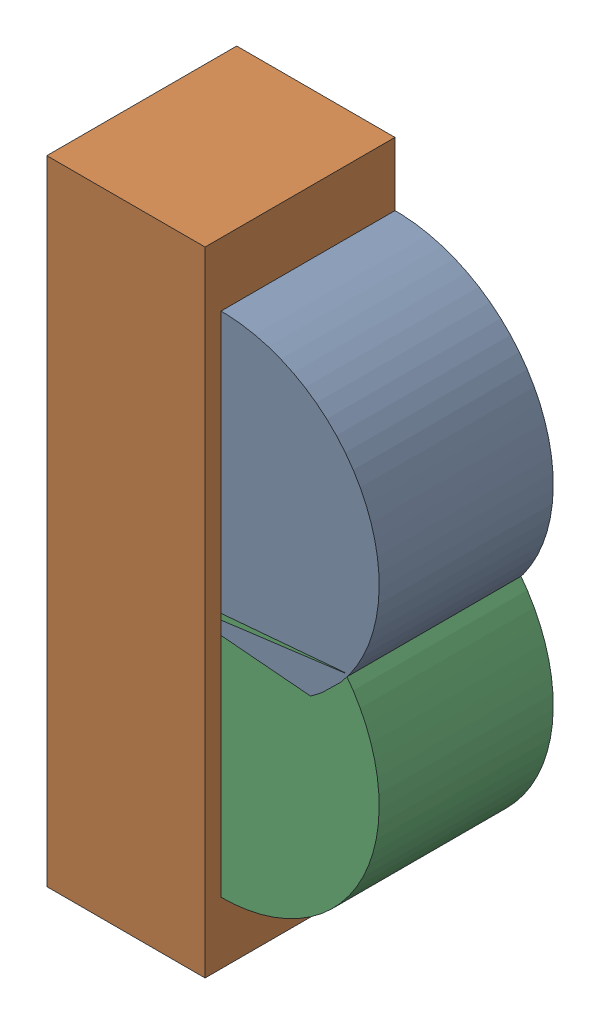
SolidWorks assembly D24, configuration Default. Lengths in mm.
Overall size (1 2 0.6).
6 component instances, 2 part files, 0 mates.
Components (placement in the parent):
- 786389736-1: 786389736 [Default] at (134.8 45.25 0) x (0 1 0) z (0 0 1) size (1 1 0.55)
  - Cylinder-1: Cylinder [Default] at origin size (1 1 0.55)
- 836753648-1: 836753648 [Default] at (134.55 44.95 0) size (0.5 2 0.6)
  - Extruded_33-1: Extruded_33 [Default] at origin size (0.5 2 0.6)
- 786389736-2: 786389736 [Default] at (134.8 44.6461 0) x (0 1 0) z (0 0 1) size (1 1 0.55)
  - Cylinder-1: Cylinder [Default] at origin size (1 1 0.55)
